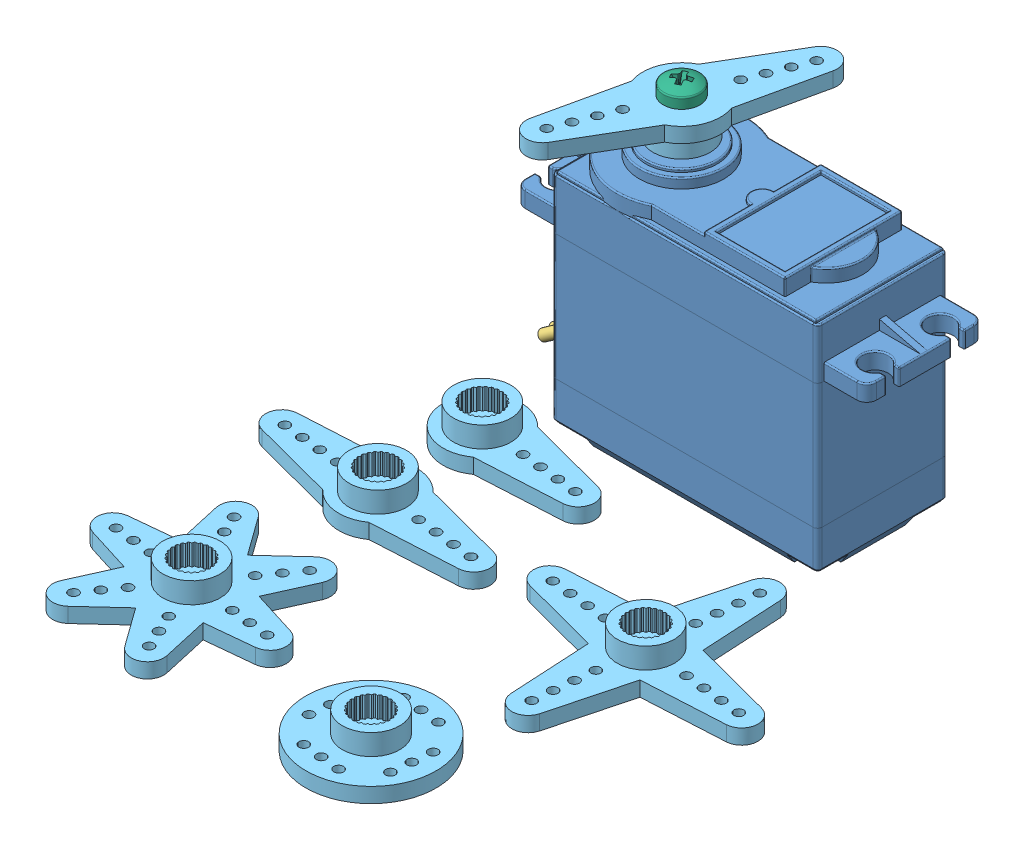
SolidWorks assembly MG996R Servo Motor, configuration Default. Lengths in mm.
Overall size (81.78 47.35 97.04).
14 component instances, 6 part files, 29 mates.
Components (placement in the parent):
- Case-1: Case [Default] at origin size (54 39 20)
- Output Shaft-1: Output Shaft [Default] at (-10.45 9.35 0) x (0.84541 0 0.534117) z (-0.534117 0 0.84541) size (13.78 15.2 13.78)
- Rubber Wire Cable Sleeve-1: Rubber Wire Cable Sleeve [Default] at (-18.2 -12.025 0) size (15.24 5.03 7.75)
- Pan Head Cross Screw M1.6-1: Pan Head Cross Screw M1.6 [Default] at (-17.575 12.35 7.125) x (0 1 0) z (0.509945 0 0.860207) size (32.17 3.2 3.2)
- Pan Head Cross Screw M1.6-2: Pan Head Cross Screw M1.6 [Default] at (17.575 12.35 7.125) x (0 1 0) z (0.498431 0 0.86693) size (32.17 3.2 3.2)
- Pan Head Cross Screw M1.6-3: Pan Head Cross Screw M1.6 [Default] at (17.575 12.35 -7.125) x (0 1 0) z (0.499198 0 0.866488) size (32.17 3.2 3.2)
- Pan Head Cross Screw M1.6-4: Pan Head Cross Screw M1.6 [Default] at (-17.575 12.35 -7.125) x (0 1 0) z (0.500246 0 0.865884) size (32.17 3.2 3.2)
- Servo Horns-1: Servo Horns [2 Horns] at (-10.45 25.7 0) x (-0.366242 0 0.930519) z (0.930519 0 0.366242) size (38 5.5 12)
- Pan Head Cross Screw M3-1: Pan Head Cross Screw M3 [Default] at (-10.45 20.85 0) x (0 -1 0) z (0.893136 0 -0.449786) size (8.51 5.6 5.6)
- Servo Horns-2: Servo Horns [1 Horn] at (-24.387 -17 16.7031) x (0.994889 0 0.100979) z (-0.100979 0 0.994889) size (25 5.5 12)
- Servo Horns-3: Servo Horns [2 Horns] at (-23.734 -17 33.4052) x (0.994889 0 0.100979) z (-0.100979 0 0.994889) size (38 5.5 12)
- Servo Horns-4: Servo Horns [4 Horns] at (17.6195 -17 33.5795) x (0.994889 0 0.100979) z (-0.100979 0 0.994889) size (38 5.5 38)
- Servo Horns-5: Servo Horns [6 Horns] at (-25.9857 -17 59.7933) x (0.994889 0 0.100979) z (-0.100979 0 0.994889) size (32 5.5 28.38)
- Servo Horns-6: Servo Horns [Circular Horn] at (8.0165 -17 66.2028) x (0.994889 0 0.100979) z (-0.100979 0 0.994889) size (20 5.5 20)
Mates (geometry in assembly coordinates):
- Concentric1: concentric aligned: cylinder of Case-1 through (-10.45 -18.151 0) axis (0 1 0) radius 3.25; cylinder of Output Shaft-1 through (-10.45 14.8629 0) axis (0 1 0) radius 3
- Distance1: distance = 3.7 mm aligned: plane of Output Shaft-1 through (-8.9705 24.55 0.9347) normal (0 1 0); plane of Case-1 through (-10.45 20.85 0) normal (0 1 0)
- Coincident1: coincident anti-aligned: plane of Case-1 through (0 -13.4 0) normal (0 1 0); plane of Rubber Wire Cable Sleeve-1 through (-20.45 -13.4 2.9) normal (0 -1 0)
- Coincident2: coincident anti-aligned: plane of Case-1 through (-20.45 -13.4 -2.9) normal (0 0 1); plane of Rubber Wire Cable Sleeve-1 through (-20.45 -13.4 -2.9) normal (0 0 -1)
- Coincident4: coincident anti-aligned: plane of Case-1 through (-20.45 -18.15 10) normal (-1 0 0); plane of Rubber Wire Cable Sleeve-1 through (-20.45 -12.025 0) normal (1 0 0)
- Concentric2: concentric aligned: cylinder of Case-1 through (-17.575 19.632 7.125) axis (0 -1 0) radius 1.125; cylinder of Pan Head Cross Screw-1 through (-17.575 9.998 7.125) axis (0 -1 0) radius 1.6
- Screw1: screw = 0.35 mm aligned: cylinder of Case-1 through (-17.575 16.632 7.125) axis (0 -1 0) radius 0.8; cylinder of Pan Head Cross Screw-1 through (-17.575 9.998 7.125) axis (0 -1 0) radius 0.8
- Coincident5: coincident anti-aligned: plane of Case-1 through (-17.575 -16.65 7.125) normal (0 -1 0); plane of Pan Head Cross Screw-1 through (-17.167 -16.65 7.8132) normal (0 1 0)
- Concentric3: concentric aligned: cylinder of Case-1 through (17.575 19.632 7.125) axis (0 -1 0) radius 1.125; cylinder of Pan Head Cross Screw-2 through (17.575 9.998 7.125) axis (0 -1 0) radius 1.6
- Screw2: screw = 0.35 mm aligned: cylinder of Case-1 through (17.575 16.632 7.125) axis (0 -1 0) radius 0.8; cylinder of Pan Head Cross Screw-2 through (17.575 9.998 7.125) axis (0 -1 0) radius 0.8
- Coincident6: coincident anti-aligned: plane of Case-1 through (17.575 -16.65 7.125) normal (0 -1 0); plane of Pan Head Cross Screw-2 through (17.9737 -16.65 7.8185) normal (0 1 0)
- Concentric4: concentric aligned: cylinder of Case-1 through (17.575 19.632 -7.125) axis (0 -1 0) radius 1.125; cylinder of Pan Head Cross Screw-3 through (17.575 9.998 -7.125) axis (0 -1 0) radius 1.6
- Screw3: screw = 0.35 mm aligned: cylinder of Case-1 through (17.575 16.632 -7.125) axis (0 -1 0) radius 0.8; cylinder of Pan Head Cross Screw-3 through (17.575 9.998 -7.125) axis (0 -1 0) radius 0.8
- Coincident7: coincident anti-aligned: plane of Case-1 through (17.575 -16.65 -7.125) normal (0 -1 0); plane of Pan Head Cross Screw-3 through (17.9744 -16.65 -6.4318) normal (0 1 0)
- Concentric5: concentric aligned: cylinder of Case-1 through (-17.575 19.632 -7.125) axis (0 -1 0) radius 1.125; cylinder of Pan Head Cross Screw-4 through (-17.575 9.998 -7.125) axis (0 -1 0) radius 1.6
- Screw4: screw = 0.35 mm aligned: cylinder of Case-1 through (-17.575 16.632 -7.125) axis (0 -1 0) radius 0.8; cylinder of Pan Head Cross Screw-4 through (-17.575 9.998 -7.125) axis (0 -1 0) radius 0.8
- Coincident8: coincident anti-aligned: plane of Case-1 through (-17.575 -16.65 -7.125) normal (0 -1 0); plane of Pan Head Cross Screw-4 through (-17.1748 -16.65 -6.4323) normal (0 1 0)
- Concentric6: concentric aligned: cylinder of Output Shaft-1 through (-10.45 14.8629 0) axis (0 1 0) radius 2.5; cylinder of Servo Horns-1 through (-10.45 24.55 0) axis (0 1 0) radius 1.5
- Coincident9: coincident anti-aligned: plane of Output Shaft-1 through (-10.2677 9.349 -2.9945) normal (0.731335 0 -0.682019); plane of Servo Horns-1 through (-10.1667 21.35 -2.8861) normal (-0.731335 0 0.682019)
- Coincident10: coincident anti-aligned: plane of Output Shaft-1 through (-8.9705 24.55 0.9347) normal (0 1 0); plane of Servo Horns-1 through (-10.45 24.55 0) normal (0 -1 0)
- Concentric7: concentric aligned: cylinder of Servo Horns-1 through (-10.45 24.55 0) axis (0 1 0) radius 1.5; cylinder of Pan Head Cross Screw M3-1 through (-10.45 23.202 0) axis (0 1 0) radius 2.8
- Screw5: screw = 0.5 mm aligned: cylinder of Output Shaft-1 through (-10.45 14.8629 0) axis (0 1 0) radius 1.5; cylinder of Pan Head Cross Screw M3-1 through (-10.45 23.202 0) axis (0 1 0) radius 1.5
- Coincident11: coincident anti-aligned: plane of Servo Horns-1 through (-10.45 26.85 0) normal (0 1 0); plane of Pan Head Cross Screw M3-1 through (-9.1103 26.85 -0.6747) normal (0 -1 0)
- Coincident12: coincident aligned: plane of Case-1 through (0 -18.15 0) normal (0 -1 0); plane of Servo Horns-2 through (-24.387 -18.15 16.7031) normal (0 -1 0)
- Coincident13: coincident aligned: plane of Case-1 through (0 -18.15 0) normal (0 -1 0); plane of Servo Horns-4 through (17.6195 -18.15 33.5795) normal (0 -1 0)
- Coincident14: coincident aligned: plane of Case-1 through (0 -18.15 0) normal (0 -1 0); plane of Servo Horns-2 through (-24.387 -18.15 16.7031) normal (0 -1 0)
- Coincident15: coincident aligned: plane of Case-1 through (0 -18.15 0) normal (0 -1 0); plane of Servo Horns-3 through (-23.734 -18.15 33.4052) normal (0 -1 0)
- Coincident16: coincident aligned: plane of Case-1 through (0 -18.15 0) normal (0 -1 0); plane of Servo Horns-6 through (8.0165 -18.15 66.2028) normal (0 -1 0)
- Coincident17: coincident aligned: plane of Case-1 through (0 -18.15 0) normal (0 -1 0); plane of Servo Horns-5 through (-25.9857 -18.15 59.7933) normal (0 -1 0)
